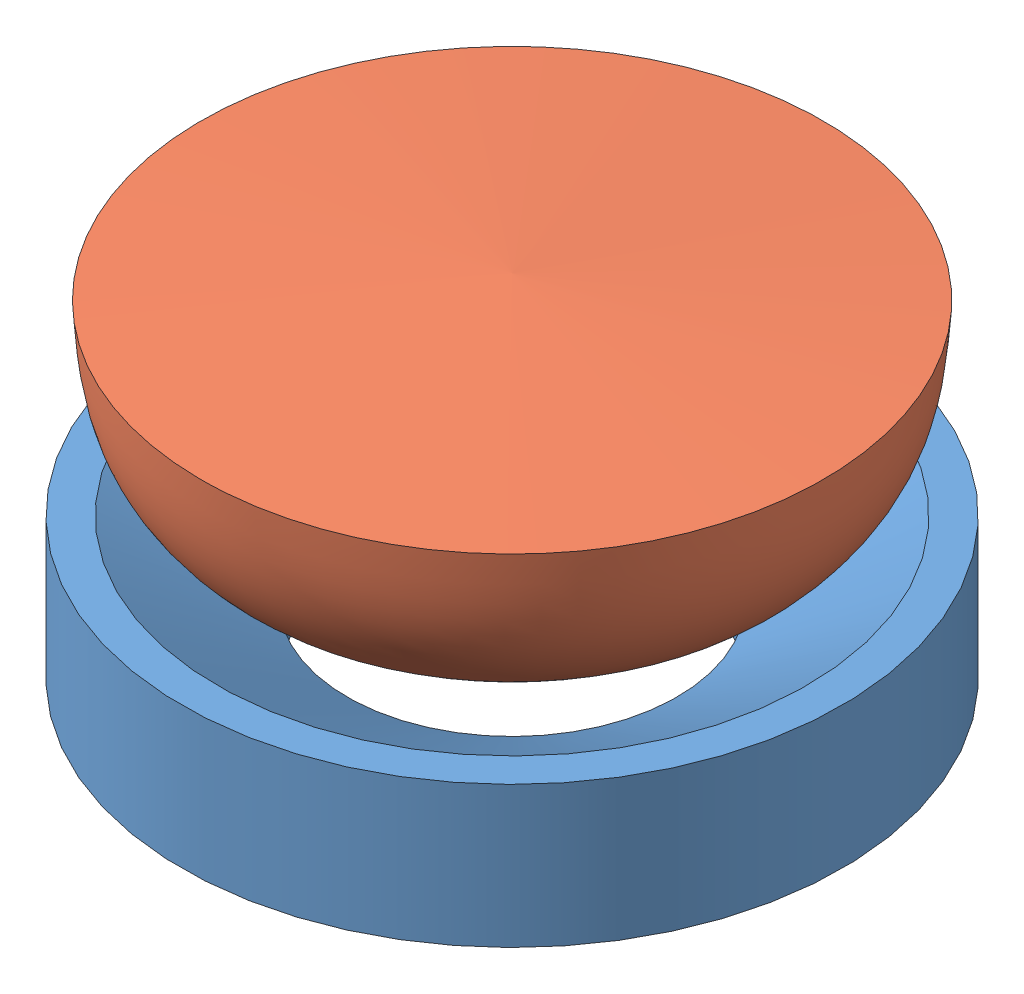
SolidWorks assembly Test Assembly, configuration Default. Lengths in mm.
Overall size (181.54 97.74 182.46).
2 component instances, 2 part files, 1 mates.
Components (placement in the parent):
- No2 Tank Coupler-1: No2 Tank Coupler [Default] at (-44.2573 5.005 10.9791) x (-0.021287 0 0.999773) z (-0.999773 0 -0.021287) size (177.8 38.1 177.8)
- NOS Bottle_PatchedModel Top model-1: NOS Bottle_PatchedModel Top model [Default] at (-44.1694 69.7675 10.3432) x (0.001315 0.999301 0.037359) z (0.035157 -0.037382 0.998682) size (73.04 172.45 172.33)
Mates (geometry in assembly coordinates):
- Concentric2: concentric: cylinder of No2 Tank Coupler-1 through (-44.2573 49.6734 10.9791) axis (0 1 0) radius 88.9; circle of NOS Bottle_PatchedModel Top model-1
